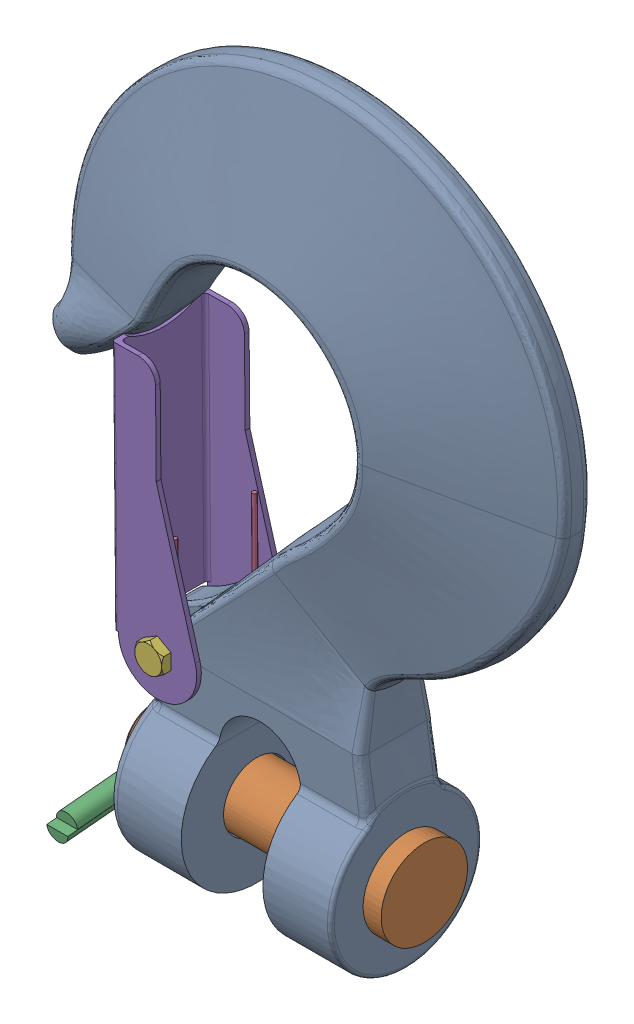
SolidWorks assembly G70_38, configuration Default. Lengths in mm.
Overall size (95.94 133.63 37.63).
4 component instances, 4 part files, 0 mates.
Components (placement in the parent):
- G70_38_1-1: G70_38_1 [Default] at (-8.4901 22.057 -14.2744) size (95.94 133.63 27.43)
- G70-PIN-1: G70-PIN [Default] at (-10.0522 -48.2629 -14.2744) x (1 0 0) z (0 0.995724 0.092378) size (49.25 15.7 15.7)
- 90520A161_1004-1045 Carbon Steel Cotter Pins-1: 90520A161_1004-1045 Carbon Steel Cotter Pins [Default] at (-30.6135 -50.0988 5.5149) x (0 -0.092378 0.995724) z (-1 0 0) size (37.07 7.82 3.81)
- 3526T11_Spring Latch Kit for Lifting Hook with Pinhole-1: 3526T11_Spring Latch Kit for Lifting Hook with Pinhole [Default] at (-25.5427 -13.7194 -14.2744) x (0 0 -1) z (-0.999962 -0.008727 0) size (20.42 52.32 15.07)
